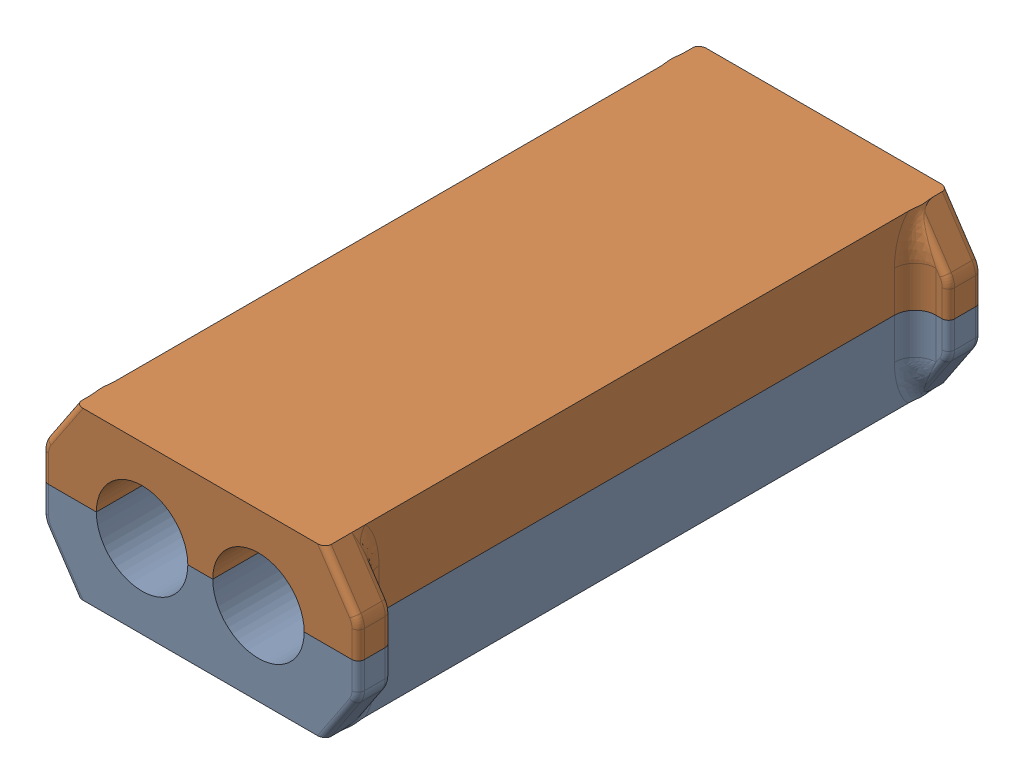
SolidWorks assembly FullAssembly, configuration Default. Lengths in mm.
Overall size (76 40.43 150).
2 component instances, 2 part files, 4 mates.
Components (placement in the parent):
- MoldTop-1: MoldTop [Default] at origin size (76 20.21 150)
- MoldBottom-1: MoldBottom [Default] at (0 40 0) x (-1 0 0) z (0 0 1) size (76 25.21 150)
Mates (geometry in assembly coordinates):
- Coincident1: coordinate: point of MoldTop-1
- Coincident2: coincident: plane of MoldTop-1 through (30 0 75) normal (1 0 0); plane of MoldBottom-1 through (30 28.9068 75) normal (1 0 0)
- Coincident3: coincident: plane of MoldTop-1 through (14 20 75) normal (0 0 1); plane of MoldBottom-1 through (-14 28.9068 75) normal (0 0 1)
- Coincident4: coincident anti-aligned: plane of MoldTop-1 through (-25 20 75) normal (0 1 0); plane of MoldBottom-1 through (-30 20 75) normal (0 -1 0)
